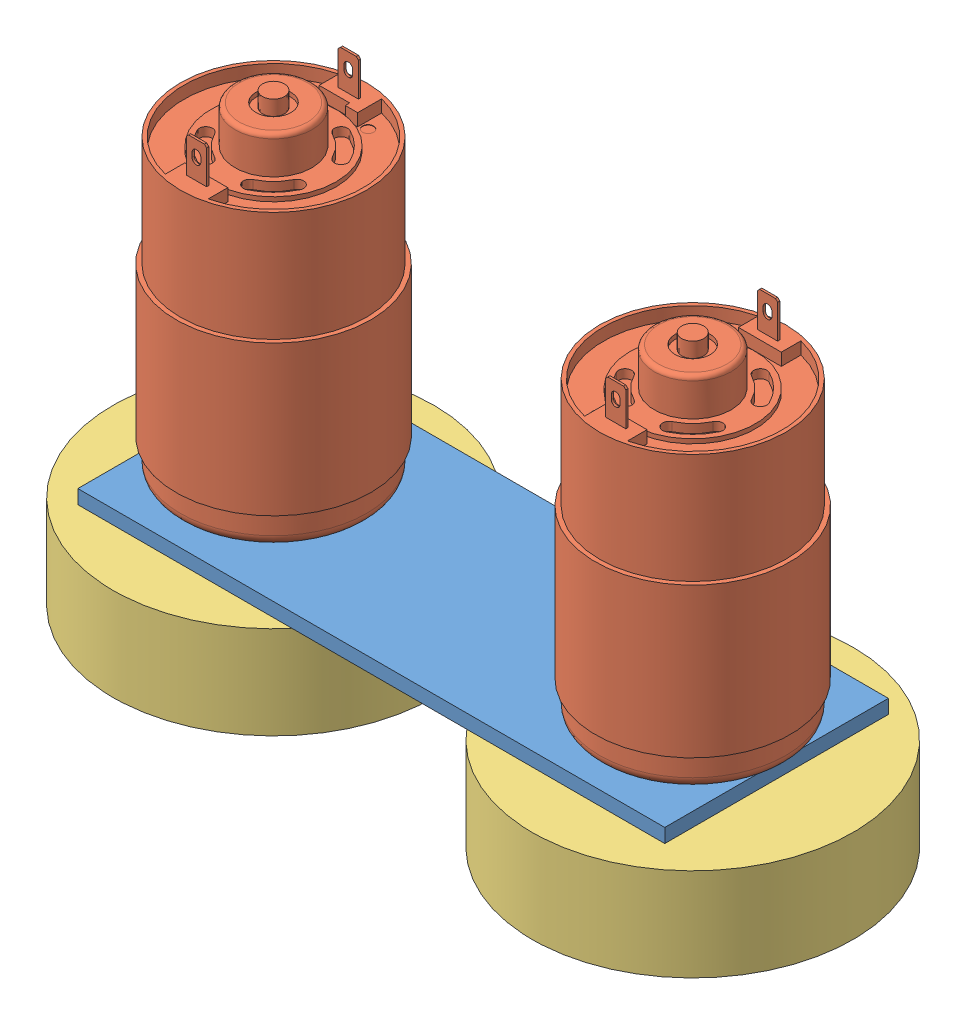
SolidWorks assembly Assem1, configuration Default. Lengths in mm.
Overall size (168.15 101.28 72.9).
5 component instances, 3 part files, 10 mates.
Components (placement in the parent):
- SpinMotorMk1-1: SpinMotorMk1 [Default] at (64.8809 64.5804 121.8401) size (133.35 3.17 50.8)
- Vex217-4347-STEP-20160210-1: Vex217-4347-STEP-20160210 [Default] at (17.2559 67.7554 121.8401) x (0 1 0) z (-1 0 0) size (88 44.3 44.3)
- Vex217-4347-STEP-20160210-2: Vex217-4347-STEP-20160210 [Default] at (112.5059 67.7554 121.8401) x (0 1 0) z (1 0 0) size (88 44.3 44.3)
- TESTWHEEL-1: TESTWHEEL [Default] at (17.2559 41.6734 121.8401) size (72.9 21.08 72.9)
- TESTWHEEL-2: TESTWHEEL [Default] at (112.5059 41.6734 121.8401) size (72.9 21.08 72.9)
Mates (geometry in assembly coordinates):
- Coincident1: coincident anti-aligned: plane of SpinMotorMk1-1 through (64.8809 67.7554 121.8401) normal (0 1 0); plane of Vex217-4347-STEP-20160210-1 through (17.2559 67.7554 112.9401) normal (0 -1 0)
- Parallel1: parallel anti-aligned: plane of SpinMotorMk1-1 through (-1.7941 67.7554 147.2401) normal (0 0 1); plane of Vex217-4347-STEP-20160210-1
- Slot2: slot anti-aligned: plane of SpinMotorMk1-1 through (26.7809 64.5804 112.3151) normal (0 0 1); cylinder of Vex217-4347-STEP-20160210-1 through (17.2559 67.7554 121.8401) axis (0 -1 0) radius 8.9; cylinder of SpinMotorMk1-1 through (17.2559 64.5804 121.8401) axis (0 1 0) radius 9.525
- Coincident3: coincident anti-aligned: plane of SpinMotorMk1-1 through (64.8809 67.7554 121.8401) normal (0 1 0); plane of Vex217-4347-STEP-20160210-2 through (112.5059 67.7554 130.7401) normal (0 -1 0)
- Slot3: slot anti-aligned: plane of SpinMotorMk1-1 through (102.9809 64.5804 112.3151) normal (0 0 1); cylinder of Vex217-4347-STEP-20160210-2 through (112.5059 67.7554 121.8401) axis (0 -1 0) radius 8.9; cylinder of SpinMotorMk1-1 through (102.9809 64.5804 121.8401) axis (0 1 0) radius 9.525
- Parallel3: parallel aligned: plane of SpinMotorMk1-1 through (-1.7941 67.7554 147.2401) normal (0 0 1); plane of Vex217-4347-STEP-20160210-2
- Concentric1: concentric anti-aligned: cylinder of Vex217-4347-STEP-20160210-1 through (17.2559 67.7554 121.8401) axis (0 -1 0) radius 2.5; circle of TESTWHEEL-1
- Coincident4: coincident anti-aligned: plane of Vex217-4347-STEP-20160210-1 through (17.2559 62.7554 119.3401) normal (0 -1 0); plane of TESTWHEEL-1 through (17.2559 62.7554 121.8401) normal (0 1 0)
- Concentric2: concentric anti-aligned: circle of Vex217-4347-STEP-20160210-2; circle of TESTWHEEL-2
- Coincident5: coincident anti-aligned: plane of Vex217-4347-STEP-20160210-2 through (112.5059 62.7554 124.3401) normal (0 -1 0); plane of TESTWHEEL-2 through (112.5059 62.7554 121.8401) normal (0 1 0)
